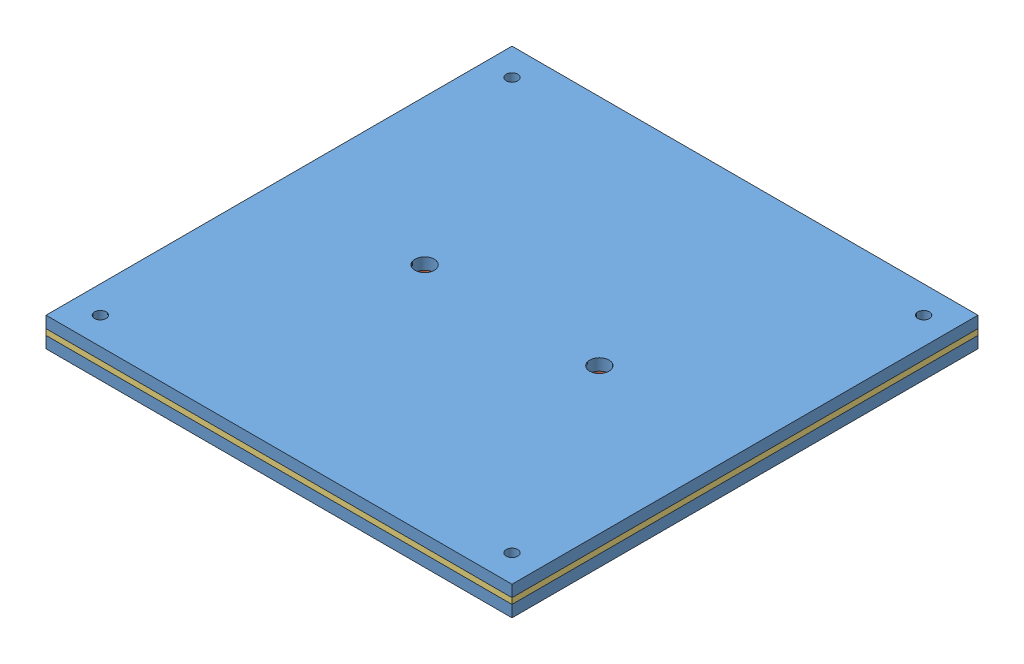
SolidWorks assembly assembly, configuration Default. Lengths in mm.
Overall size (120 7.5 120).
5 component instances, 3 part files, 6 mates.
Components (placement in the parent):
- lower_upper_layer-1: lower_upper_layer [Default] at (38.6999 58.0181 97.4345) size (120 3 120)
- ring1-1: ring1 [Default] at (16.1999 61.0181 97.4345) size (9 1.5 9)
- ring1-2: ring1 [Default] at (61.1999 61.0181 97.4345) size (9 1.5 9)
- middle_layer-1: middle_layer [Default] at (38.6999 61.0181 97.4345) size (120 1.5 120)
- lower_upper_layer-2: lower_upper_layer [Default] at (38.6999 62.5181 97.4345) size (120 3 120)
Mates (geometry in assembly coordinates):
- Coincident1: coincident aligned: line of lower_upper_layer-1 through (-21.3001 61.0181 157.4345) axis (1 0 0); line of middle_layer-1 through (-21.3001 61.0181 157.4345) axis (1 0 0)
- Coincident2: coincident aligned: line of lower_upper_layer-1 through (98.6999 61.0181 157.4345) axis (0 0 -1); line of middle_layer-1 through (98.6999 61.0181 157.4345) axis (0 0 -1)
- Coincident4: coincident anti-aligned: circle of lower_upper_layer-1; circle of ring1-1
- Coincident5: coincident anti-aligned: circle of lower_upper_layer-1; circle of ring1-2
- Coincident6: coincident aligned: line of middle_layer-1 through (98.6999 62.5181 37.4345) axis (-1 0 0); line of lower_upper_layer-2 through (98.6999 62.5181 37.4345) axis (-1 0 0)
- Coincident7: coincident aligned: line of middle_layer-1 through (-21.3001 62.5181 37.4345) axis (0 0 1); line of lower_upper_layer-2 through (-21.3001 62.5181 37.4345) axis (0 0 1)
